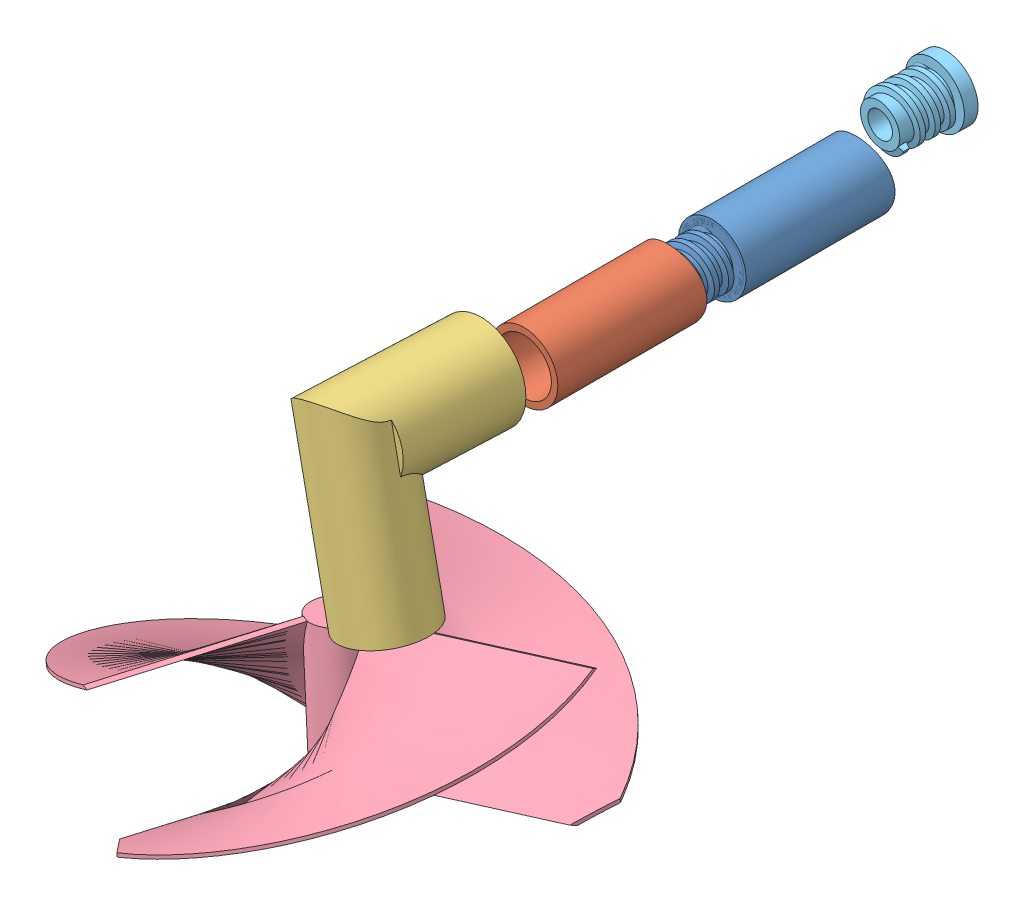
SolidWorks assembly 装配体1, configuration 默认. Lengths in mm.
Overall size (200.32 167.92 317.11).
5 component instances, 5 part files, 0 mates.
Components (placement in the parent):
- 连接潜艇-1: 连接潜艇 [默认] at (62.0069 12.4039 -20.421) size (26 26 78.09)
- 连电机-1: 连电机 [默认] at (61.3638 11.9715 51.218) size (26 26 58.09)
- 电机套-2: 电机套 [默认] at (65.1924 -43.7683 160.0565) x (0.029507 -0.013572 -0.999472) z (-0.223653 0.974467 -0.019835) size (62 35 75)
- 打印的潜艇螺旋桨  大-1: 打印的潜艇螺旋桨  大 [默认] at (34.3801 -60.9033 147.7954) x (0.238942 -0.038969 -0.970252) z (0.123142 -0.989911 0.070085) size (160.35 160.43 60.69)
- 螺丝-1: 螺丝 [默认] at (51.5353 14.205 -43.0198) x (-0.953473 -0.295674 -0.058878) z (0.052696 0.02884 -0.998194) size (24 24 25)
